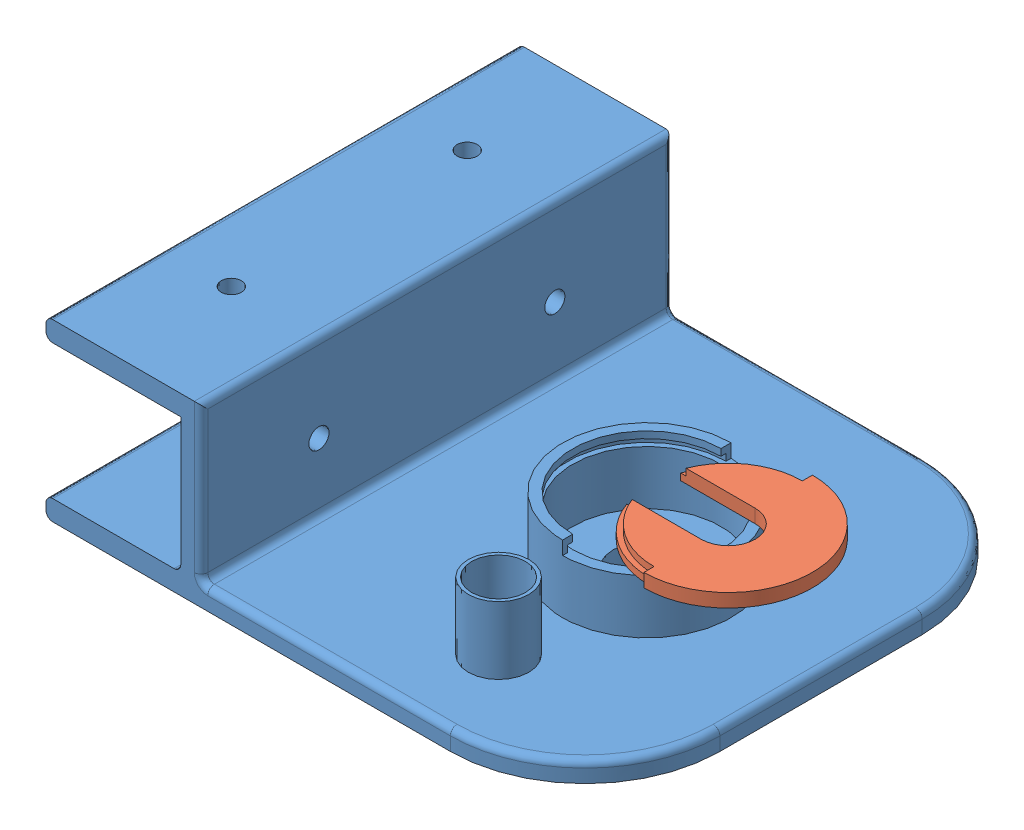
SolidWorks assembly bearing adapter ass, configuration Default. Lengths in mm.
Overall size (80 26 70).
2 component instances, 2 part files, 2 mates.
Components (placement in the parent):
- Part5-1: Part5 [Default] at (16.4557 29.1291 68.2225) size (80 26 70)
- part 6-1: part 6 [Default] at (41.8657 41.1944 67.413) size (23.55 2 25)
Mates (geometry in assembly coordinates):
- Coincident1: coincident anti-aligned: plane of Part5-1 through (30.6057 12.1782 68.2225) normal (1 0 0); plane of part 6-1 through (30.6057 42.1291 68.1329) normal (-1 0 0)
- Coincident2: coincident anti-aligned: plane of Part5-1 through (16.4557 40.1291 68.2225) normal (0 1 0); plane of part 6-1 through (30.6057 40.1291 68.1329) normal (0 -1 0)
